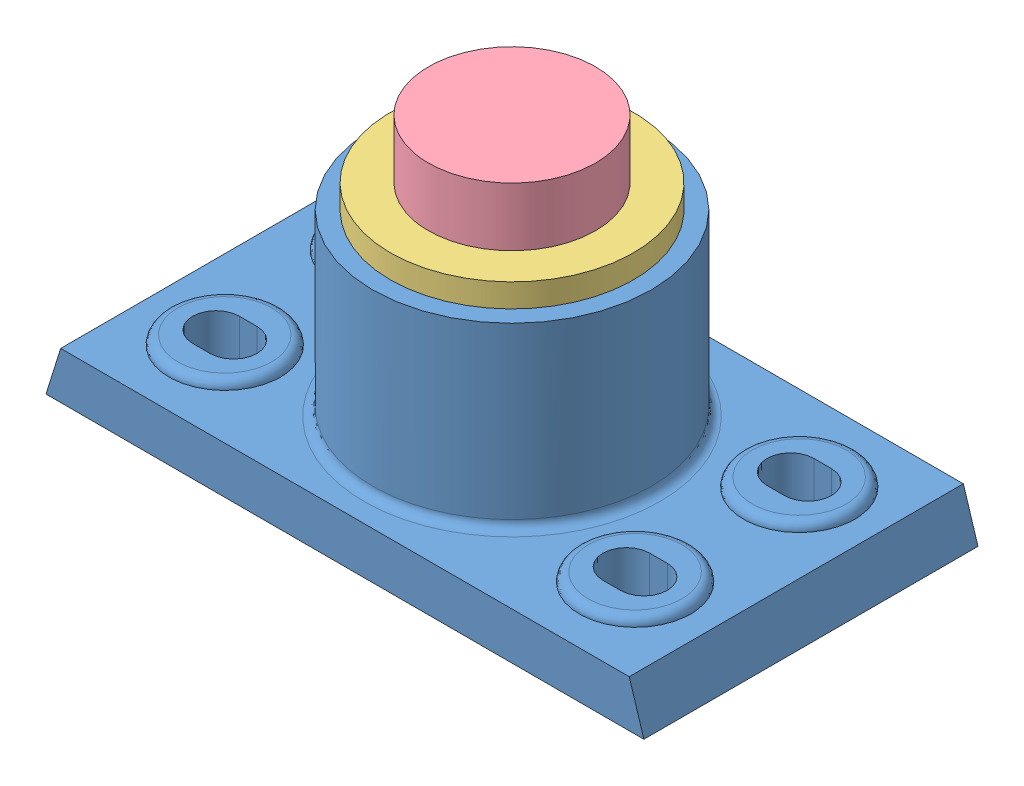
SolidWorks assembly Assem1, configuration Default. Lengths in mm.
Overall size (204 105 114).
5 component instances, 5 part files, 10 mates.
Components (placement in the parent):
- body-2: body [Default] at (82.7756 64.3554 155.5378) size (204 77 114)
- pin-2: pin [Default] at (60.7756 75.3554 155.5378) x (1 0 0) z (0 1 0) size (3 3 10)
- bush-1: bush [Default] at (82.7756 72.3554 155.5378) size (83 77 83)
- shaft-1: shaft [Default] at (82.7756 74.3554 155.5378) x (0.993335 0 0.115264) z (-0.115264 0 0.993335) size (57 95 57)
- pad-1: pad [Default] at (82.7756 72.3554 155.5378) size (44 13 44)
Mates (geometry in assembly coordinates):
- Concentric3: concentric anti-aligned: cylinder of body-2 through (60.7756 80.3554 155.5378) axis (0 1 0) radius 1.5; cylinder of pin-2 through (60.7756 85.3554 155.5378) axis (0 -1 0) radius 1.5
- Coincident2: coincident: cone of body-2 through (60.7756 75.3554 155.5378) axis (0 -1 0); circle of pin-2
- Concentric4: concentric aligned: cylinder of bush-1 through (82.7756 281.8635 155.5378) axis (0 1 0) radius 22; cylinder of pad-1 through (82.7756 288.6144 155.5378) axis (0 1 0) radius 22
- Concentric5: concentric aligned: cylinder of bush-1 through (60.7756 244.8496 155.5378) axis (0 -1 0) radius 1.5; cylinder of pad-1 through (60.7756 244.8496 155.5378) axis (0 -1 0) radius 1.5
- Coincident3: coincident aligned: plane of bush-1 through (113.7756 239.8496 155.5378) normal (0 -1 0); plane of pad-1 through (82.7756 239.8496 155.5378) normal (0 -1 0)
- Concentric6: concentric: cylinder of bush-1 through (82.7756 114.3693 155.5378) axis (0 1 0) radius 22; cylinder of shaft-1 through (82.7756 318.7197 155.5378) axis (0 -1 0) radius 22
- Concentric12: concentric aligned: cylinder of pin-2 through (60.7756 85.3554 155.5378) axis (0 -1 0) radius 1.5; cylinder of pad-1 through (60.7756 244.8496 155.5378) axis (0 -1 0) radius 1.5
- Concentric13: concentric anti-aligned: cylinder of body-2 through (82.7756 64.3554 155.5378) axis (0 -1 0) radius 32.5; cylinder of bush-1 through (82.7756 281.8635 155.5378) axis (0 1 0) radius 29.5
- Coincident6: coincident anti-aligned: plane of body-2 through (35.2756 141.3554 155.5378) normal (0 1 0); plane of bush-1 through (124.2756 141.3554 155.5378) normal (0 -1 0)
- Coincident7: coincident anti-aligned: plane of bush-1 through (104.7756 149.3554 155.5378) normal (0 1 0); plane of shaft-1 through (82.7756 149.3554 155.5378) normal (0 -1 0)
